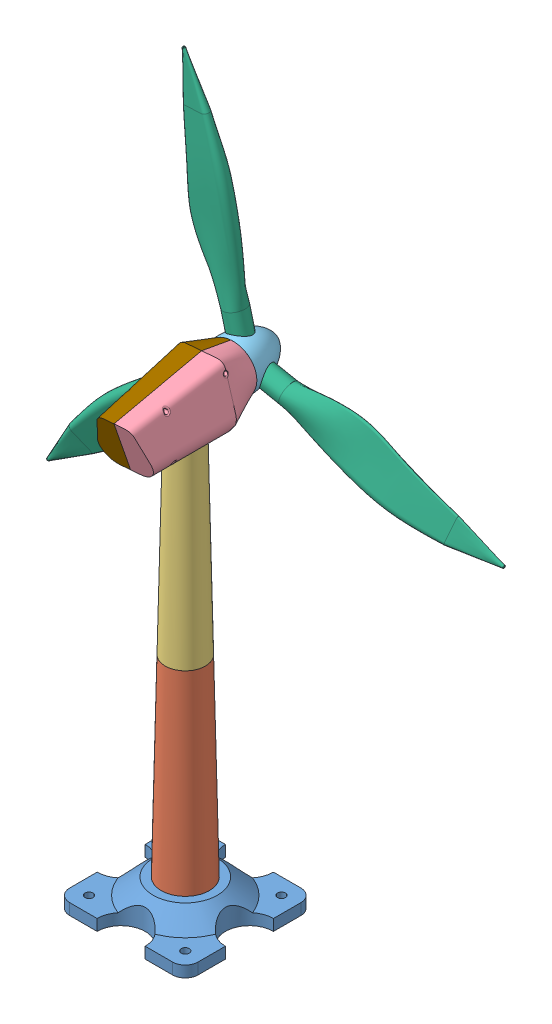
SolidWorks assembly assembly2, configuration Default. Lengths in mm.
Overall size (356.53 547.35 150.54).
16 component instances, 10 part files, 29 mates.
Components (placement in the parent):
- 1.base-1: 1.base [Default] at origin size (101.6 21.59 101.6)
- 4.lower must-1: 4.lower must [Default] at (0 8.89 0) x (0 1 0) z (0 0 1) size (165.1 38.1 38.1)
- 5.upper mast-1: 5.upper mast [Default] at (0 173.99 0) x (0 1 0) z (0.66371 0 -0.74799) size (165.1 31.76 31.76)
- 8.housing-2: 8.housing [Default] at (-1.2177 349.25 -14.1276) x (-0.996306 0 0.085876) z (-0.085876 0 -0.996306) size (28.03 49.56 102.82)
- 2.rotor-1: 2.rotor [Default] at (-3.399 349.25 -39.4338) x (0.085876 0 0.996306) z (-0.970153 -0.227618 0.083622) size (38.1 38.53 38.1)
- 3.blade-1: 3.blade [Default] at (-6.2176 356.67 -51.9379) x (-0.168144 -0.058912 0.984) z (-0.959322 -0.219862 -0.17709) size (18.85 190.5 45.63)
- 3.blade-2: 3.blade [Default] at (-10.0277 344.0379 -51.6095) x (0.259328 -0.188804 0.947155) z (0.636025 -0.704627 -0.3146) size (18.85 190.5 45.63)
- 3.blade-3: 3.blade [Default] at (2.7766 347.0421 -52.7132) x (0.157666 0.247716 0.955917) z (0.256619 0.924489 -0.281898) size (18.85 190.5 45.63)
- 6.shaft-1: 6.shaft [Default] at (-3.6308 349.25 -42.1238) x (0.426837 -0.90358 -0.036791) z (0.085876 0 0.996306) size (9.65 9.65 85)
- 7.washer-3: 7.washer [Default] at (-1.5449 349.25 -17.9235) x (0.173001 0.984809 -0.014912) z (0.085876 0 0.996306) size (22.86 22.86 7.62)
- 7.washer-4: 7.washer [Default] at (2.2723 349.25 26.3623) x (0.173001 0.984809 -0.014912) z (0.085876 0 0.996306) size (22.86 22.86 7.62)
- 8.housing-1: 8.housing [Default] at (-1.2177 349.25 -14.1276) x (-0.996306 0 0.085876) z (-0.085876 0 -0.996306) size (28.03 49.56 102.82)
- 7.washer-1: 7.washer [Default] at (-1.5449 349.25 -17.9235) x (-0.797892 0.598865 0.068774) z (0.085876 0 0.996306) size (22.86 22.86 7.62)
- 7.washer-2: 7.washer [Default] at (2.2723 349.25 26.3623) x (-0.797892 0.598865 0.068774) z (0.085876 0 0.996306) size (22.86 22.86 7.62)
- Mirror8.housing-4: Mirror8.housing [Default] at (-1.2177 349.25 -14.1276) x (0.996306 0 -0.085876) z (0.085876 0 0.996306)
- Mirror9.housing-2: Mirror9.housing [Default] at (-1.2177 349.25 -14.1276) x (0.996306 0 -0.085876) z (0.085876 0 0.996306) size (28.03 49.56 102.82)
Mates (geometry in assembly coordinates):
- Coincident1: coincident aligned: plane of 1.base-1 through (0 0 0) normal (0 0 1)
- Coincident2: coincident aligned: plane of 1.base-1 through (0 0 0) normal (0 1 0)
- Coincident3: coincident aligned: plane of 1.base-1 through (0 0 0) normal (1 0 0)
- Concentric1: concentric anti-aligned: cylinder of 1.base-1 through (0 0 0) axis (0 1 0) radius 19.05; cylinder of 4.lower must-1 through (0 8.89 0) axis (0 -1 0) radius 19.05
- Concentric3: concentric aligned: cone of 4.lower must-1 through (0 173.99 0) axis (0 1 0); cone of 5.upper mast-1 through (0 326.39 0) axis (0 1 0)
- Concentric4: concentric anti-aligned: cylinder of 5.upper mast-1 through (0 173.99 0) axis (0 -1 0) radius 4.83; cylinder of 9.housing-1 through (0 339.09 0) axis (0 1 0) radius 4.83
- Tangent1: tangent anti-aligned: plane of 5.upper mast-1 through (-3.2057 326.39 3.6128) normal (0 1 0); face of ?
- Concentric5: concentric anti-aligned: cylinder of 9.housing-1 through (-3.6905 349.25 -42.8159) axis (-0.085876 0 -0.996306) radius 6.35; cylinder of 2.rotor-1 through (-4.4896 349.25 -52.0869) axis (0.085876 0 0.996306) radius 4.826
- Coincident5: coincident anti-aligned: plane of 9.housing-1 through (-3.399 349.25 -39.4338) normal (-0.085876 0 -0.996306); plane of 2.rotor-1 through (-7.7191 367.7999 -39.0614) normal (0.085876 0 0.996306)
- Coincident6: coincident anti-aligned: circle of 2.rotor-1; plane of 3.blade-1 through (-6.2176 356.67 -51.9379) normal (0.226777 -0.97375 -0.019547)
- Concentric6: concentric anti-aligned: cylinder of 2.rotor-1 through (-6.2176 356.67 -51.9379) axis (-0.226777 0.97375 0.019547) radius 8.255; cylinder of 3.blade-1 through (-11.9778 381.4032 -51.4414) axis (0.226777 -0.97375 -0.019547) radius 8.255
- Angle1: planar angle = 1.308997 rad anti-aligned: plane of 3.blade-1 through (-6.2176 356.67 -51.9379) normal (-0.959322 -0.219862 -0.17709); plane of 2.rotor-1 through (-3.399 349.25 -39.4338) normal (0.085876 0 0.996306)
- Coincident8: coincident anti-aligned: plane of 4.lower must-1 through (0 173.99 0) normal (0 1 0); plane of 5.upper mast-1 through (-10.5397 173.99 11.8781) normal (0 -1 0)
- Coincident9: coincident anti-aligned: plane of 1.base-1 through (-40.8 8.89 -40.8) normal (0 1 0); circle of 4.lower must-1
- Concentric7: concentric aligned: cylinder of 9.housing-1 through (-3.6905 349.25 -42.8159) axis (-0.085876 0 -0.996306) radius 6.35; cylinder of 6.shaft-1 through (3.6686 349.25 42.5622) axis (-0.085876 0 -0.996306) radius 4.825
- Distance1: distance = 10 mm anti-aligned: plane of 2.rotor-1 through (-4.4896 349.25 -52.0869) normal (0.085876 0 0.996306); plane of 6.shaft-1 through (-3.6308 349.25 -42.1238) normal (-0.085876 0 -0.996306)
- Concentric8: concentric aligned: cylinder of 9.housing-1 through (-3.6905 349.25 -42.8159) axis (-0.085876 0 -0.996306) radius 11.43; cylinder of 8.washer-1 through (-0.8905 349.25 -10.3317) axis (-0.085876 0 -0.996306) radius 11.43
- Coincident11: coincident anti-aligned: plane of 9.housing-1 through (-1.5449 360.68 -17.9235) normal (0.085876 0 0.996306); plane of 8.washer-1 through (-1.5449 349.25 -17.9235) normal (-0.085876 0 -0.996306)
- Concentric9: concentric aligned: cylinder of 9.housing-1 through (-3.6905 349.25 -42.8159) axis (-0.085876 0 -0.996306) radius 11.43; cylinder of 8.washer-2 through (2.9267 349.25 33.9541) axis (-0.085876 0 -0.996306) radius 11.43
- Coincident12: coincident anti-aligned: plane of 9.housing-1 through (2.9267 355.6 33.9541) normal (-0.085876 0 -0.996306); plane of 8.washer-2 through (2.9267 349.25 33.9541) normal (0.085876 0 0.996306)
- Coincident15: coincident anti-aligned: plane of 2.rotor-1 through (-7.7191 367.7999 -39.0614) normal (0.085876 0 0.996306); plane of 8.housing-1 through (-3.399 349.25 -39.4338) normal (-0.085876 0 -0.996306)
- Concentric13: concentric aligned: cylinder of 6.shaft-1 through (3.6686 349.25 42.5622) axis (-0.085876 0 -0.996306) radius 4.825; cylinder of 8.housing-1 through (-3.6905 349.25 -42.8159) axis (-0.085876 0 -0.996306) radius 6.35
- Concentric14: concentric anti-aligned: cylinder of 2.rotor-1 through (-4.4896 349.25 -52.0869) axis (0.085876 0 0.996306) radius 4.826; cylinder of 6.shaft-1 through (3.6686 349.25 42.5622) axis (-0.085876 0 -0.996306) radius 4.825
- Concentric15: concentric anti-aligned: cylinder of 5.upper mast-1 through (0 173.99 0) axis (0 -1 0) radius 4.83; cylinder of 8.housing-1 through (0 339.09 0) axis (0 1 0) radius 4.83
- Coincident16: coincident: plane of 5.upper mast-1 through (-3.2057 326.39 3.6128) normal (0 1 0); line of 8.housing-1 through (0.4148 326.39 4.8122) axis (0.085876 0 0.996306)
- Concentric16: concentric aligned: cylinder of 6.shaft-1 through (3.6686 349.25 42.5622) axis (-0.085876 0 -0.996306) radius 4.825; cylinder of 7.washer-1 through (-0.8905 349.25 -10.3317) axis (-0.085876 0 -0.996306) radius 6.35
- Coincident17: coincident anti-aligned: plane of 8.housing-1 through (-1.5449 360.68 -17.9235) normal (0.085876 0 0.996306); plane of 7.washer-1 through (-1.5449 349.25 -17.9235) normal (-0.085876 0 -0.996306)
- Concentric171: concentric aligned: cylinder of 6.shaft-1 through (3.6686 349.25 42.5622) axis (-0.085876 0 -0.996306) radius 4.825; cylinder of 7.washer-2 through (2.9267 349.25 33.9541) axis (-0.085876 0 -0.996306) radius 11.43
- Coincident18: coincident anti-aligned: plane of 8.housing-1 through (2.9267 355.6 33.9541) normal (-0.085876 0 -0.996306); plane of 7.washer-2 through (2.9267 349.25 33.9541) normal (0.085876 0 0.996306)
